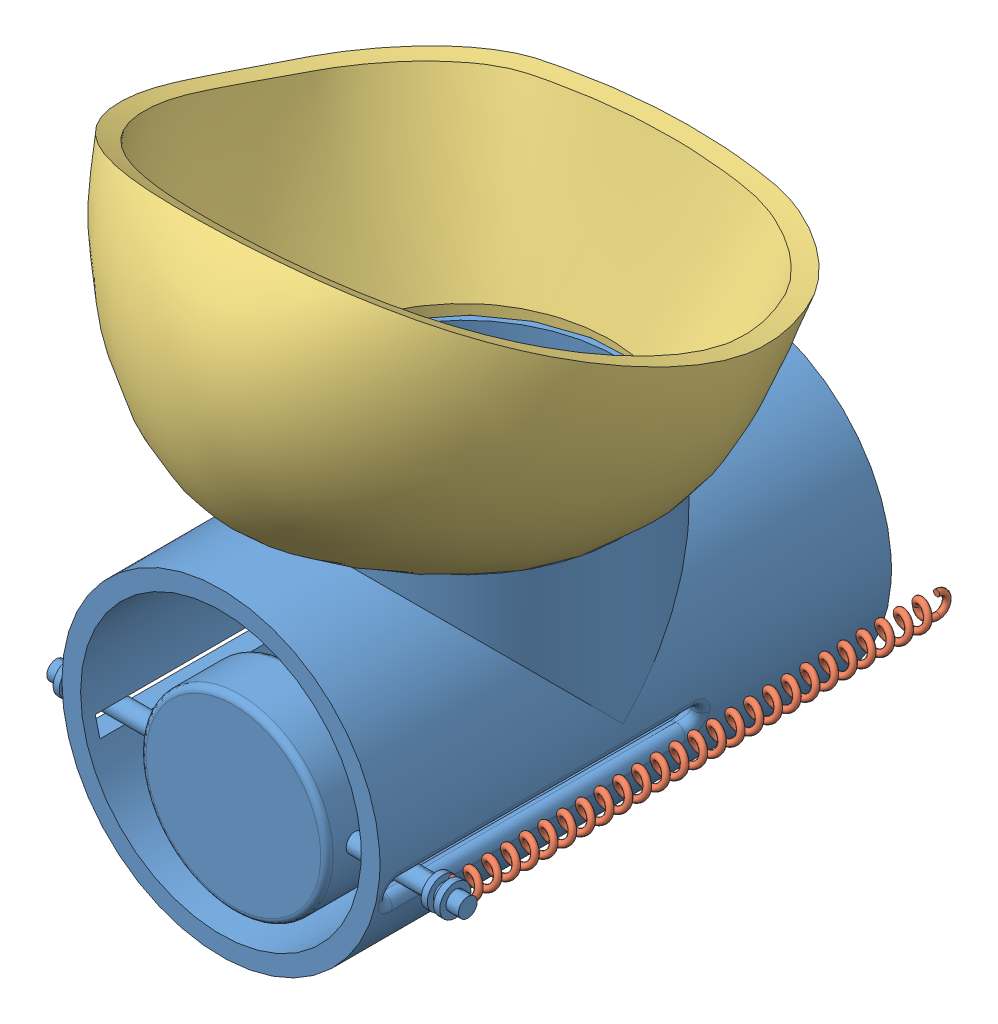
SolidWorks assembly spring assembly to the cylinder_11.06pm, configuration Default. Lengths in mm.
Overall size (95.03 106.15 97.92).
4 component instances, 3 part files, 6 mates.
Components (placement in the parent):
- bottom part-1: bottom part [Default] at (16.4612 51.9827 29.7161) size (66 51.5 82)
- spring-1: spring [Default] at (46.4612 46.5132 103.532) x (0 0.999821 0.018905) z (-1 0 0) size (5.47 82.4 5.47)
- spring-3: spring [Default] at (-13.5388 46.4913 103.5318) x (0 -0.999986 -0.005211) z (1 0 0) size (5.47 82.4 5.47)
- funnel-1: funnel [Default] at (16.4612 127.9827 72.7161) x (0.043655 0 0.999047) z (0.999047 0 -0.043655) size (88.22 55.15 91.27)
Mates (geometry in assembly coordinates):
- Concentric1: concentric: cylinder of bottom part-1 through (-16.5388 46.483 105.1317) axis (1 0 0) radius 1.5; circle of spring-1
- Concentric2: concentric: circle of bottom part-1; circle of spring-1
- Coincident1: coincident: plane of bottom part-1 through (46.4612 46.483 105.1317) normal (-1 0 0); circle of spring-1
- Concentric4: concentric: cylinder of bottom part-1 through (-16.5388 46.483 105.1317) axis (1 0 0) radius 1.5; circle of spring-3
- Coincident2: coincident: plane of bottom part-1 through (-13.5388 46.483 105.1317) normal (1 0 0); circle of spring-3
- Coincident3: coincident: circle of bottom part-1; circle of funnel-1
